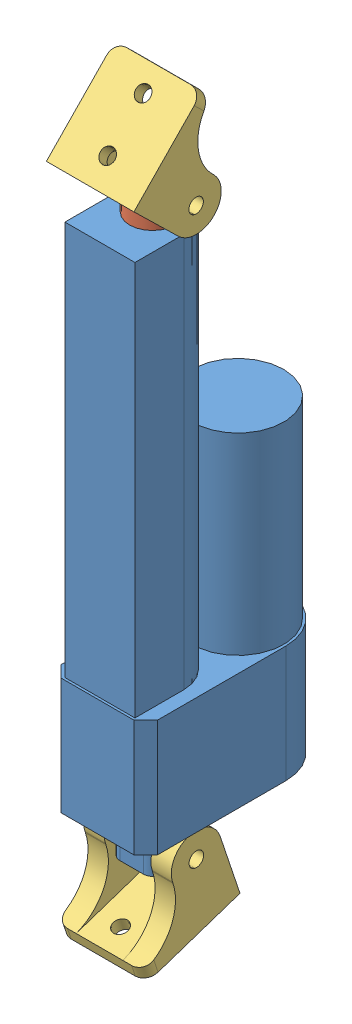
SolidWorks assembly Actuator, configuration Default. Lengths in mm.
Overall size (41.91 323.93 91.74).
4 component instances, 3 part files, 5 mates.
Components (placement in the parent):
- Actuator Draft-1: Actuator Draft [Default] at (-7.6865 -102.2801 28.8302) size (41.91 242.57 82.04)
- Piston draft-1: Piston draft [Default] at (-37.5678 -6.7761 37.6899) x (0 0 -1) z (1 0 0) size (19.81 147.83 19.81)
- Actuator Bracket Draft-1: Actuator Bracket Draft [Default] at (-39.1411 -142.5762 36.7994) x (1 0 0) z (0 -0.316975 0.948434) size (38.1 38.1 42.67)
- Actuator Bracket Draft-2: Actuator Bracket Draft [Default] at (-39.2419 156.964 51.4677) x (1 0 0) z (0 0.716107 -0.69799) size (38.1 38.1 42.67)
Mates (geometry in assembly coordinates):
- Concentric1: concentric anti-aligned: cylinder of Actuator Draft-1 through (-37.5678 -6.7761 37.6899) axis (0 1 0) radius 9.906; cylinder of Piston draft-1 through (-37.5678 120.2239 37.6899) axis (0 -1 0) radius 9.906
- Parallel1: parallel aligned: cylinder of Actuator Draft-1 through (-26.5188 -114.2181 37.6899) axis (-1 0 0) radius 3.81; cylinder of Piston draft-1 through (-21.8198 132.1619 37.6899) axis (-1 0 0) radius 3.81
- Coincident1: coincident anti-aligned: plane of Actuator Draft-1 through (-37.5678 -6.7761 37.6899) normal (0 1 0); plane of Piston draft-1 through (-37.5678 -6.7761 37.6899) normal (0 -1 0)
- Concentric3: concentric anti-aligned: cylinder of Actuator Draft-1 through (-26.5188 -114.2181 37.6899) axis (-1 0 0) radius 3.81; cylinder of Actuator Bracket Draft-1 through (-18.4391 -114.2181 37.6899) axis (1 0 0) radius 3.175
- Concentric4: concentric anti-aligned: cylinder of Piston draft-1 through (-21.8198 132.1619 37.6899) axis (-1 0 0) radius 3.81; cylinder of Actuator Bracket Draft-2 through (-18.5398 132.1619 37.6899) axis (1 0 0) radius 3.175
